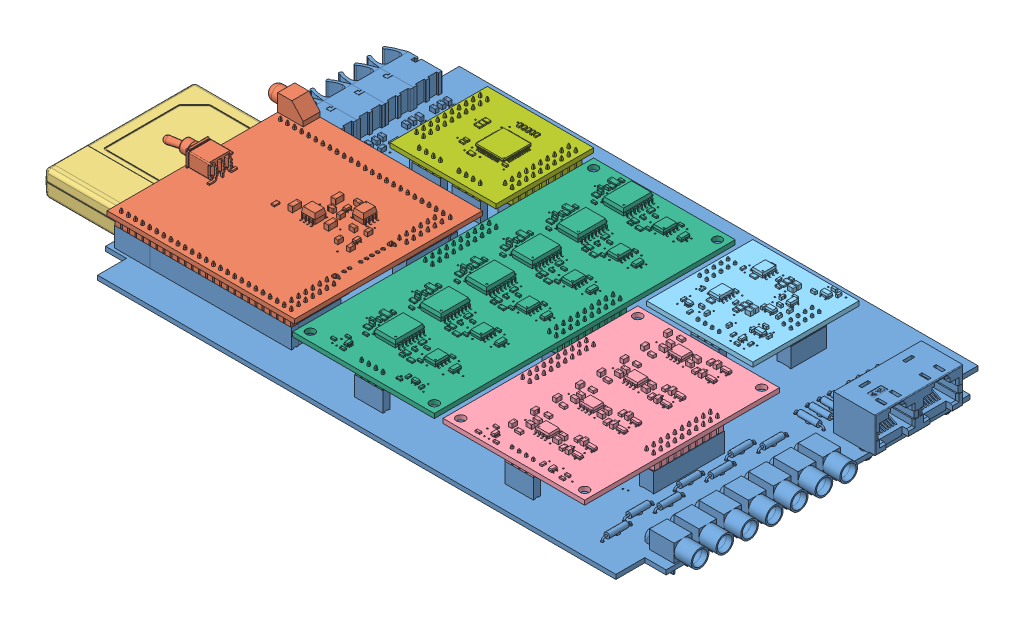
SolidWorks assembly PRiME_Preamp, configuration Default. Lengths in mm.
Overall size (215.67 21.29 129.79).
13 component instances, 7 part files, 20 mates.
Components (placement in the parent):
- MW_PRiME-MB-1: MW_PRiME-MB [Default] at origin size (212.12 17.21 129.79)
  - PRiME-MB-2: PRiME-MB [Default] at (-192.4001 -1.6 0) x (1 0 0) z (0 1 0) size (212.12 129.79 17.21)
- MW_PRiME_PowerModule-1: MW_PRiME_PowerModule [Default] at (-196.5901 11.067 -10.66) x (0 0 1) z (-1 0 0) size (67.31 17.07 76.5)
  - PRiME_PowerModule-1: PRiME_PowerModule [Default] at (-67.31 -1.6 0) x (1 0 0) z (0 1 0) size (67.31 76.5 17.07)
- CC2300_nominal-2: CC2300_nominal [Default] at (-138.8772 2.6328 -43.6707) x (0 0 -1) z (1 0 0) size (54 9.11 86.51) (hidden)
- MW_PRiME_HFModule-2: MW_PRiME_HFModule [Default] at (-71.7501 11.14 -76.2) x (-1 0 0) z (0 0 -1) size (50.8 12.58 69.85)
  - PRiME_HFModule-1: PRiME_HFModule [Default] at (-50.8 -1.6 0) x (1 0 0) z (0 1 0) size (50.8 69.85 12.58)
- MW_PRiME_PressureModule-2: MW_PRiME_PressureModule [Default] at (-71.7501 11.14 -117.48) x (-1 0 0) z (0 0 -1) size (38.1 11.66 38.1)
  - PRiME_PressureModule-1: PRiME_PressureModule [Default] at (-38.1 -1.6 0) x (1 0 0) z (0 1 0) size (38.1 38.1 11.66)
- MW_PRiME_ECGModule-2: MW_PRiME_ECGModule [Default] at (-125.7201 11.067 -114.31) x (-1 0 0) z (0 0 -1) size (50.8 13.5 107.95)
  - PRiME_ECGModule-1: PRiME_ECGModule [Default] at (-50.8 -1.6 0) x (1 0 0) z (0 1 0) size (50.8 107.95 13.5)
- MW_PRiME_ADCModule-2: MW_PRiME_ADCModule [Default] at (-167.0001 11.067 -117.48) x (-1 0 0) z (0 0 -1) size (38.1 12.15 34.92)
  - PRiME_ADCModule-2: PRiME_ADCModule [Default] at (-38.1 -1.6 0) x (1 0 0) z (0 1 0) size (38.1 34.92 12.15)
Mates (geometry in assembly coordinates):
- Coincident1: coincident aligned: plane of MW_PRiME-MB-1 through (0 0 0) normal (0 1 0); plane of assembly through (0 0 0) normal (0 1 0)
- Coincident2: coincident aligned: plane of MW_PRiME-MB-1 through (0 0 0) normal (1 0 0); plane of assembly through (0 0 0) normal (1 0 0)
- Coincident3: coincident aligned: plane of MW_PRiME-MB-1 through (0 0 0) normal (0 0 1); plane of assembly through (0 0 0) normal (0 0 1)
- Coincident27: coincident anti-aligned: plane of MW_PRiME-MB-1 through (0 7 0) normal (0 1 0); plane of MW_PRiME_PowerModule-1
- Coincident28: coincident aligned: line of MW_PRiME-MB-1 through (-193.5401 -1.6 -69.77) axis (0 1 0); line of MW_PRiME_PowerModule-1 through (-193.5401 9.467 -69.77) axis (0 1 0)
- Coincident34: coincident anti-aligned: plane of MW_PRiME_PowerModule-1 through (-196.5901 11.067 -38.2543) normal (0 0 1); plane of CC2300_nominal-2 through (-138.8772 2.6328 -38.2543) normal (0 0 -1)
- Coincident35: coincident anti-aligned: plane of MW_PRiME_PowerModule-1 through (-137.2126 11.067 -10.66) normal (-1 0 0); plane of CC2300_nominal-2 through (-137.2126 2.6328 -43.6707) normal (1 0 0)
- Coincident36: coincident anti-aligned: plane of MW_PRiME_PowerModule-1; plane of CC2300_nominal-2
- Coincident37: coincident anti-aligned: plane of MW_PRiME-MB-1 through (0 7 0) normal (0 1 0); plane of MW_PRiME_HFModule-2
- Parallel9: parallel aligned: plane of MW_PRiME-MB-1 through (0 0 0) normal (0 0 1); plane of MW_PRiME_HFModule-2 through (-71.7501 11.14 -6.35) normal (0 0 1)
- Coincident46: coincident aligned: line of MW_PRiME-MB-1 through (-50.1601 -1.6 -9.53) axis (0 1 0); line of MW_PRiME_HFModule-2 through (-50.1601 9.54 -9.53) axis (0 1 0)
- Parallel10: parallel aligned: plane of MW_PRiME-MB-1 through (0 0 -129.794) normal (0 0 -1); plane of MW_PRiME_PressureModule-2 through (-71.7501 11.14 -117.48) normal (0 0 -1)
- Coincident48: coincident aligned: line of MW_PRiME-MB-1 through (-56.5101 -1.6 -82.55) axis (0 1 0); line of MW_PRiME_PressureModule-2 through (-56.5101 9.54 -82.55) axis (0 1 0)
- Coincident51: coincident anti-aligned: plane of MW_PRiME-MB-1 through (0 7 0) normal (0 1 0); plane of MW_PRiME_PressureModule-2
- Parallel12: parallel aligned: plane of MW_PRiME-MB-1 through (0 0 0) normal (0 0 1); plane of MW_PRiME_ECGModule-2 through (-125.7201 11.067 -6.36) normal (0 0 1)
- Coincident53: coincident anti-aligned: plane of MW_PRiME-MB-1 through (0 7 0) normal (0 1 0); plane of MW_PRiME_ECGModule-2
- Coincident54: coincident aligned: line of MW_PRiME-MB-1 through (-104.1301 -1.6 -9.53) axis (0 1 0); line of MW_PRiME_ECGModule-2 through (-104.1301 9.467 -9.53) axis (0 1 0)
- Coincident59: coincident aligned: line of MW_PRiME-MB-1 through (-159.7001 -1.6 -85.73) axis (0 1 0); line of MW_PRiME_ADCModule-2 through (-159.7001 9.467 -85.73) axis (0 1 0)
- Coincident60: coincident anti-aligned: plane of MW_PRiME-MB-1 through (0 7 0) normal (0 1 0); plane of MW_PRiME_ADCModule-2
- Parallel15: parallel aligned: plane of MW_PRiME-MB-1 through (0 0 -129.794) normal (0 0 -1); plane of MW_PRiME_ADCModule-2 through (-167.0001 11.067 -117.48) normal (0 0 -1)
